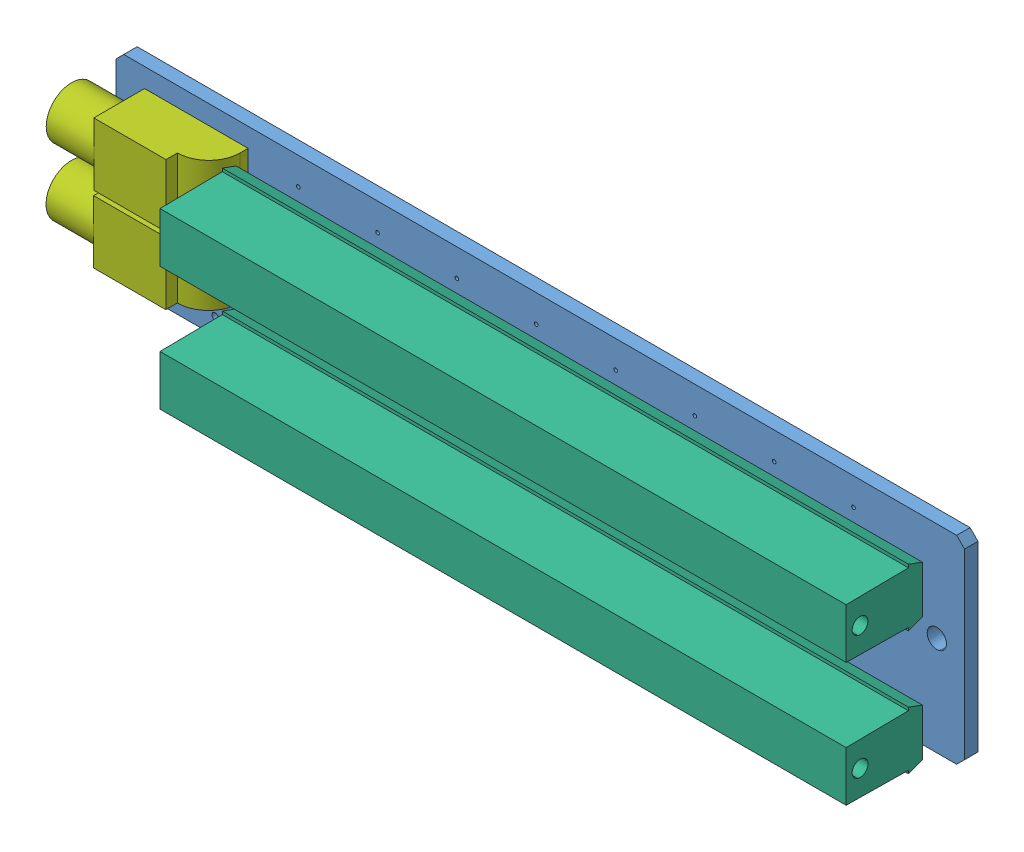
SolidWorks assembly pigtail_v1_revA_1, configuration Default. Lengths in mm.
Overall size (108.6 25 14.62).
23 component instances, 8 part files, 0 mates.
Components (placement in the parent):
- Board_1_1-1: Board_1_1 [Default] at (0 0 -1.6916) size (107 25 1.69)
- J2_1-1: J2_1 [Default] at origin size (86.5 7.28 10.75)
  - mill-max-0908-2-15-20-75-14-11-0_1_1-1: mill-max-0908-2-15-20-75-14-11-0_1_1 [Default] at (99.1339 18.2516 2) x (0 0 1) z (1 0 0) size (3.33 1.01 1.01)
    - mill-max-0908-2-15-20-75-14-11-0_SPRING_1-1: mill-max-0908-2-15-20-75-14-11-0_SPRING_1 [Default] at (5.5978 -0.8235 -1.1087) x (0 -0.998082 0.061903) z (-1 0 0) size (0.96 0.96 3.33)
  - mill-max-0908-2-15-20-75-14-11-0_1_2-1: mill-max-0908-2-15-20-75-14-11-0_1_2 [Default] at (99.1339 18.2516 2) x (0 0 1) z (1 0 0) size (9.22 1.83 1.83)
    - mill-max-0908-2-15-20-75-14-11-0_0963-0_0963-0-00-20-00-00-13-0_1-1: mill-max-0908-2-15-20-75-14-11-0_0963-0_0963-0-00-20-00-00-13-0_1 [Default] at (0.1795 -0.8235 -1.1087) size (4.04 1.31 1.31)
    - mill-max-0908-2-15-20-75-14-11-0_0954-0_0954-0-00-20-00-00-13-0_1-1: mill-max-0908-2-15-20-75-14-11-0_0954-0_0954-0-00-20-00-00-13-0_1 [Default] at (1.9321 -0.8235 -1.1087) size (5.03 1.83 1.83)
    - mill-max-0908-2-15-20-75-14-11-0_SPRING_0975-0-00-00-75-14-45-0_1-1: mill-max-0908-2-15-20-75-14-11-0_SPRING_0975-0-00-00-75-14-45-0_1 [Default] at (5.5978 -0.8235 -1.1087) x (0 -0.998082 0.061903) z (-1 0 0) size (0.8 0.8 3.43)
    - mill-max-0908-2-15-20-75-14-11-0_0918-X_0918-7-00-20-00-00-13-0_1-1: mill-max-0908-2-15-20-75-14-11-0_0918-X_0918-7-00-20-00-00-13-0_1 [Default] at (3.9133 -0.8235 -1.1087) x (1 0 0) z (0 0.540629 0.841261) size (5.49 1.25 1.25)
  - wire_connector_1-1: wire_connector_1 [Default] at (18.525 20.2649 3.3287) x (1 0 0) z (0 -1 0) size (86.5 9.6 7.28)
- J1_1-1: J1_1 [Default] at origin size (86.5 7.28 10.75)
  - mill-max-0908-2-15-20-75-14-11-0_1_1-1: mill-max-0908-2-15-20-75-14-11-0_1_1 [Default] at (99.1339 2.6516 2) x (0 0 1) z (1 0 0) size (3.33 1.01 1.01)
    - mill-max-0908-2-15-20-75-14-11-0_SPRING_1-1: mill-max-0908-2-15-20-75-14-11-0_SPRING_1 [Default] at (5.5978 -0.8235 -1.1087) x (0 -0.998082 0.061903) z (-1 0 0) size (0.96 0.96 3.33)
  - mill-max-0908-2-15-20-75-14-11-0_1_2-1: mill-max-0908-2-15-20-75-14-11-0_1_2 [Default] at (99.1339 2.6516 2) x (0 0 1) z (1 0 0) size (9.22 1.83 1.83)
    - mill-max-0908-2-15-20-75-14-11-0_0963-0_0963-0-00-20-00-00-13-0_1-1: mill-max-0908-2-15-20-75-14-11-0_0963-0_0963-0-00-20-00-00-13-0_1 [Default] at (0.1795 -0.8235 -1.1087) size (4.04 1.31 1.31)
    - mill-max-0908-2-15-20-75-14-11-0_0954-0_0954-0-00-20-00-00-13-0_1-1: mill-max-0908-2-15-20-75-14-11-0_0954-0_0954-0-00-20-00-00-13-0_1 [Default] at (1.9321 -0.8235 -1.1087) size (5.03 1.83 1.83)
    - mill-max-0908-2-15-20-75-14-11-0_SPRING_0975-0-00-00-75-14-45-0_1-1: mill-max-0908-2-15-20-75-14-11-0_SPRING_0975-0-00-00-75-14-45-0_1 [Default] at (5.5978 -0.8235 -1.1087) x (0 -0.998082 0.061903) z (-1 0 0) size (0.8 0.8 3.43)
    - mill-max-0908-2-15-20-75-14-11-0_0918-X_0918-7-00-20-00-00-13-0_1-1: mill-max-0908-2-15-20-75-14-11-0_0918-X_0918-7-00-20-00-00-13-0_1 [Default] at (3.9133 -0.8235 -1.1087) x (1 0 0) z (0 0.540629 0.841261) size (5.49 1.25 1.25)
  - wire_connector_1-1: wire_connector_1 [Default] at (18.525 4.6649 3.3287) x (1 0 0) z (0 -1 0) size (86.5 9.6 7.28)
- J4_1-1: J4_1 [Default] at origin size (19.05 7.9 7.4)
  - Jack_PCB_1-1: Jack_PCB_1 [Default] at (7.9499 10.9619 4) x (-1 0 0) z (0 1 0) size (19.05 7.4 7.9)
- J3_1-1: J3_1 [Default] at origin size (19.05 7.9 7.4)
  - Jack_PCB_1-1: Jack_PCB_1 [Default] at (7.9749 19.4619 4) x (-1 0 0) z (0 1 0) size (19.05 7.4 7.9)
